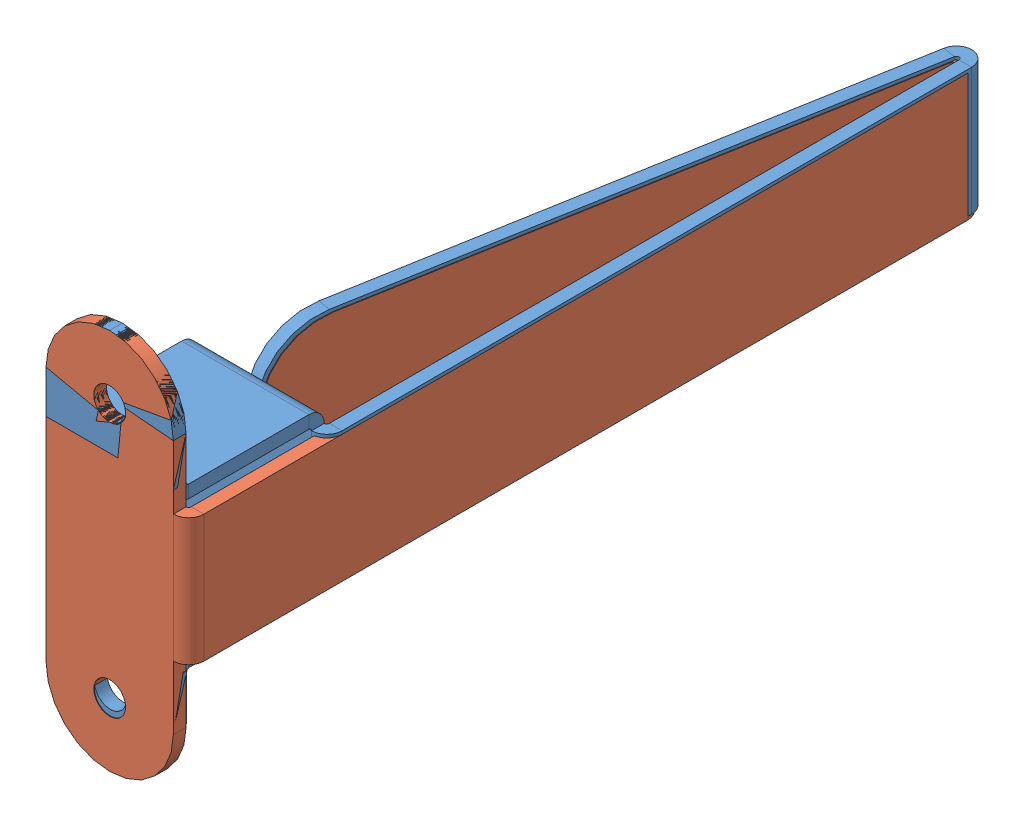
SolidWorks assembly Assem1, configuration Default. Lengths in mm.
Overall size (14.22 38.1 79.63).
2 component instances, 2 part files, 1 mates.
Components (placement in the parent):
- sheet metal prong design 2-1: sheet metal prong design 2 [Default] at (0.6205 36.5767 121.7225) size (14.22 37.53 79.63)
- sheet metal prong design 3-1: sheet metal prong design 3 [Default] at (0.6205 62.0416 110.1022) x (1 0 0) z (0 1 0) size (14.22 79.25 38.1)
Mates (geometry in assembly coordinates):
- Coincident1: coincident aligned: circle of sheet metal prong design 2-1; circle of sheet metal prong design 3-1
